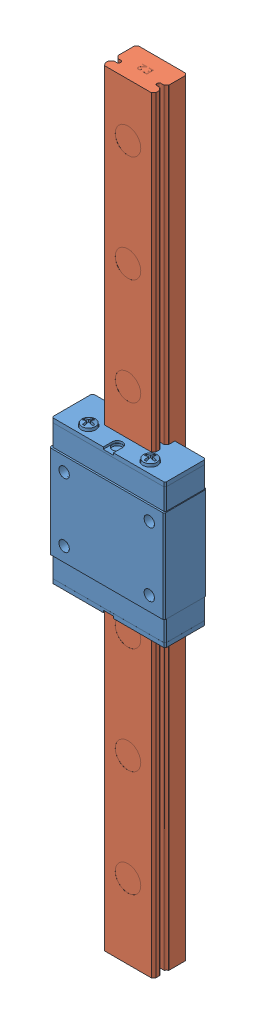
SolidWorks assembly mgn12_assy, configuration Default. Lengths in mm.
Overall size (27 107.76 13).
2 component instances, 2 part files, 2 mates.
Components (placement in the parent):
- mgn12_w-1: mgn12_w [Défaut] at (57.6179 93.1843 12.9907) size (27 35.69 10)
- mgn12_r-1: mgn12_r [Défaut] at (57.6179 0 12.9907) size (12 80 8)
Mates (geometry in assembly coordinates):
- Coaxiale1: concentric aligned: cylinder of mgn12_w-1 through (52.8537 133.9543 18.4466) axis (0 1 0) radius 0.5; cylinder of mgn12_r-1 through (52.8537 200 18.4466) axis (0 1 0) radius 0.5
- Coaxiale2: concentric aligned: circle of mgn12_w-1; cylinder of mgn12_r-1 through (62.3822 200 18.4466) axis (0 1 0) radius 0.5
